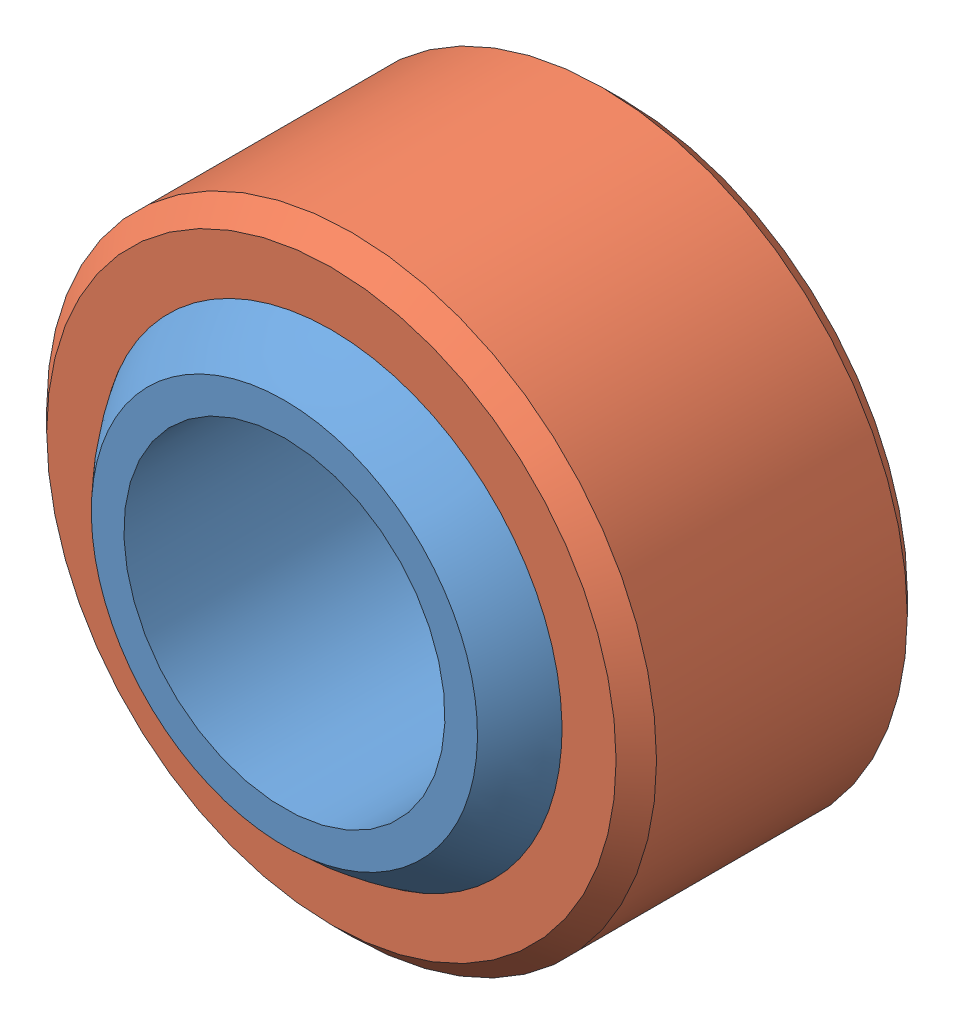
SolidWorks assembly SphericalBearing625, configuration Default. Lengths in mm.
Overall size (30.16 32.6 22.58).
2 component instances, 2 part files, 1 mates.
Components (placement in the parent):
- SphericalBearingBall625-1: SphericalBearingBall625 [Default] at origin size (26.97 32.6 22.58)
- SphericalBeaingRace625-1: SphericalBeaingRace625 [Default] at origin size (30.16 30.16 14.4)
Mates (geometry in assembly coordinates):
- Concentric1: concentric: sphere of ?; unknown of ?
